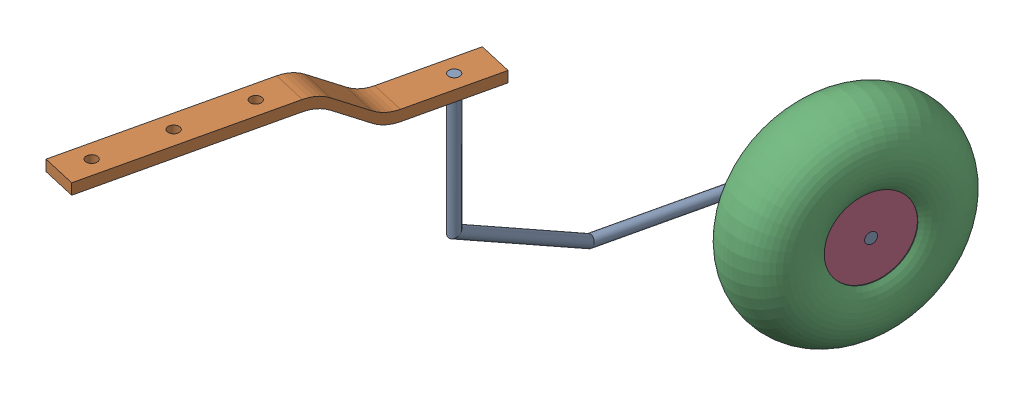
SolidWorks assembly landing_rear, configuration Default. Lengths in mm.
Overall size (47.39 74.02 141.84).
3 component instances, 3 part files, 5 mates.
Components (placement in the parent):
- Axelv2-1: Axelv2 [Default] at (14.0524 -16.0598 -6.6634) x (0.974566 0 0.2241) z (-0.2241 0 0.974566) size (20.05 42.65 59.76)
- carbon shock-1: carbon shock [Default] at (-4.924 23.5883 41.7227) x (-0.974566 0 -0.2241) z (0.2241 0 -0.974566) size (6.35 9.28 67.55)
- rearwheel-1: rearwheel [Default] at (1.6755 -16.0598 -9.5095) x (0.974566 0 0.2241) z (-0.205584 -0.398017 0.894045) size (15.46 38.24 38.24)
Mates (geometry in assembly coordinates):
- Concentric2: concentric aligned: cylinder of Axelv2-1 through (-9.4413 -1.2105 47.1997) axis (0 1 0) radius 1; cylinder of carbon shock-1 through (-9.4413 20.7598 47.1997) axis (0 1 0) radius 1
- Coincident1: coincident anti-aligned: circle of Axelv2-1; plane of carbon shock-1 through (-11.1125 25.5883 40.2997) normal (0 1 0)
- Concentric3: concentric aligned: cylinder of Axelv2-1 through (14.0524 -16.0598 -6.6634) axis (-0.974566 0 -0.2241) radius 1; cylinder of rearwheel-1 through (1.6755 -16.0598 -9.5095) axis (-0.974566 0 -0.2241) radius 1
- Coincident2: coincident aligned: plane of Axelv2-1 through (14.0524 -16.0598 -6.6634) normal (0.974566 0 0.2241); plane of rearwheel-1 through (13.9633 -15.1424 -6.2755) normal (0.974566 0 0.2241)
- Parallel1: parallel aligned: plane of carbon shock-1 through (-11.1125 23.5883 40.2997) normal (-0.974566 0 -0.2241); plane of rearwheel-1 through (1.5863 -15.1424 -9.1216) normal (-0.974566 0 -0.2241)
